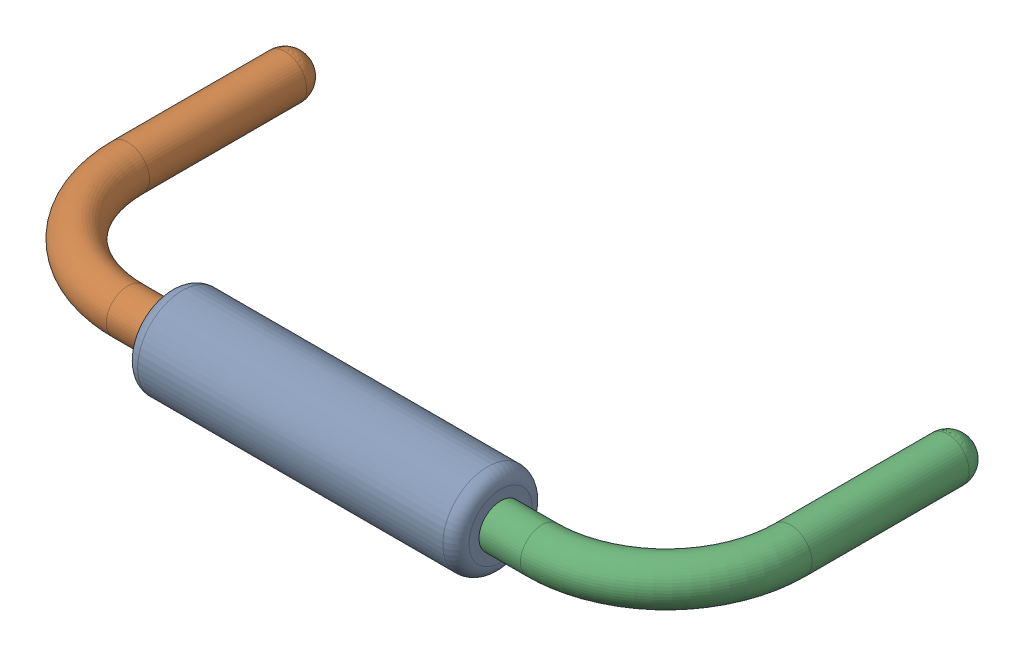
SolidWorks assembly R10, configuration Défaut. Lengths in mm.
Overall size (10.82 1.37 5.33).
4 component instances, 3 part files, 0 mates.
Components (placement in the parent):
- Open CASCADE STEP translator 6.8 1.10.1-1: Open CASCADE STEP translator 6.8 1.10.1 [Défaut] at origin size (10.82 1.37 5.33)
  - Body_1_7-1: Body_1_7 [Défaut] at origin size (5.08 1.37 1.37)
  - Pin_1_4-1: Pin_1_4 [Défaut] at origin size (3.2 0.66 4.98)
  - Pin_2_4-1: Pin_2_4 [Défaut] at (20.32 0 0) x (-1 0 0) z (0 0 1) size (3.2 0.66 4.98)
